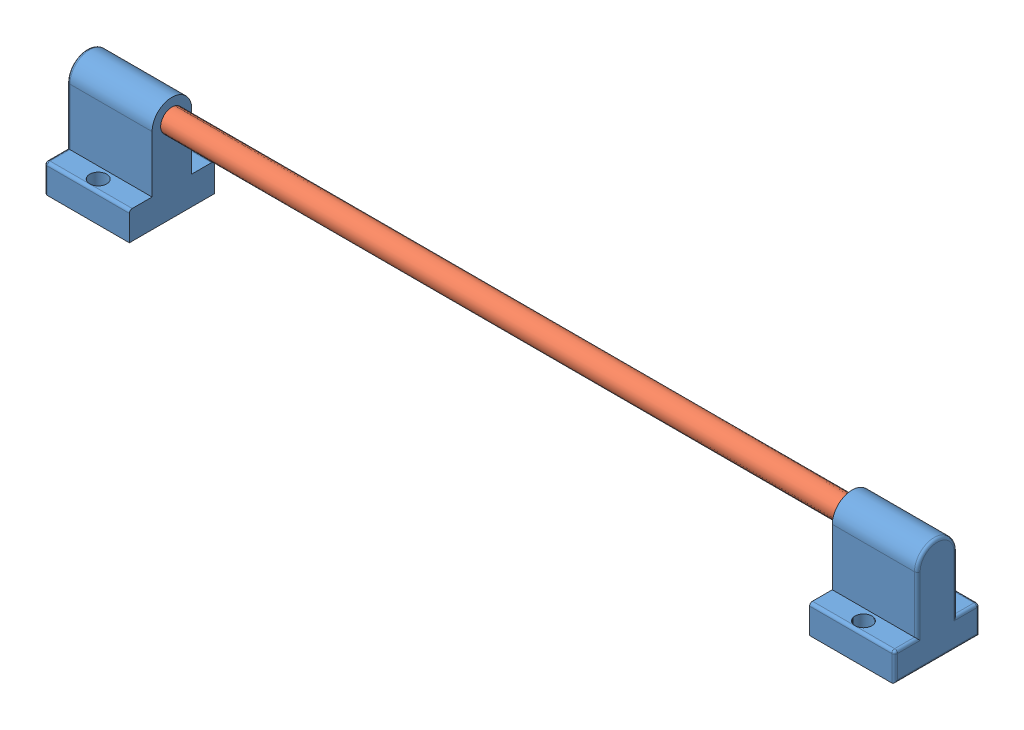
SolidWorks assembly Assem3, configuration Default. Lengths in mm.
Overall size (300 37 30).
3 component instances, 2 part files, 6 mates.
Components (placement in the parent):
- 8mmSmoothRodHolder-1: 8mmSmoothRodHolder [Default] at (-76.6784 48.5 -2.7535) size (30 37 30)
- 8mmSmoothRodHolder-3: 8mmSmoothRodHolder [Default] at (-316.6784 48.5 -2.7535) x (-1 0 0) z (0 0 -1) size (30 37 30)
- 8mmAlluminiumRod_L=29cm-1: 8mmAlluminiumRod_L=29cm [Default] at (-341.6784 48.5 -2.7535) size (290 8 8)
Mates (geometry in assembly coordinates):
- Distance1: distance = 300 mm anti-aligned: plane of 8mmSmoothRodHolder-1 through (-46.6784 48.5 -2.7535) normal (1 0 0); plane of 8mmSmoothRodHolder-3 through (-346.6784 48.5 -2.7535) normal (-1 0 0)
- Coincident2: coincident aligned: plane of 8mmSmoothRodHolder-1 through (-76.6784 18.5 12.2465) normal (0 0 1); plane of 8mmSmoothRodHolder-3 through (-316.6784 18.5 12.2465) normal (0 0 1)
- Coincident3: coincident aligned: plane of 8mmSmoothRodHolder-1 through (-76.6784 18.5 -2.7535) normal (0 -1 0); plane of 8mmSmoothRodHolder-3 through (-316.6784 18.5 -2.7535) normal (0 -1 0)
- Coincident4: coincident: plane of 8mmSmoothRodHolder-3 through (-341.6784 48.5 -2.7535) normal (1 0 0); plane of 8mmAlluminiumRod_L=29cm-1 through (-341.6784 48.5 -2.7535) normal (-1 0 0)
- Parallel1: parallel: plane of 8mmSmoothRodHolder-3 through (-341.6784 48.5 -2.7535) normal (1 0 0); plane of 8mmAlluminiumRod_L=29cm-1 through (-341.6784 48.5 -2.7535) normal (-1 0 0)
- Coincident6: coincident anti-aligned: circle of 8mmSmoothRodHolder-3; circle of 8mmAlluminiumRod_L=29cm-1
